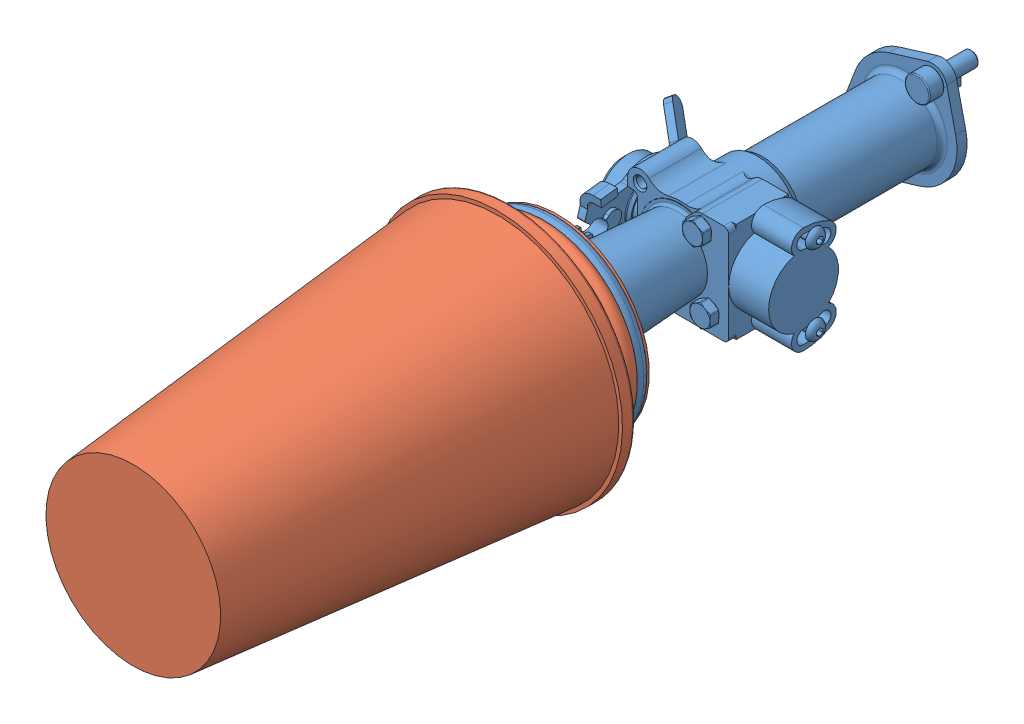
SolidWorks assembly formula_student_throttle_with_air_filter, configuration Default. Lengths in mm.
Overall size (127.6 127.6 349.5).
2 component instances, 2 part files, 2 mates.
Components (placement in the parent):
- formula_student_throttle-1: formula_student_throttle [Default] at (-37.9429 12.0312 36.252) size (78.2 75 188.5)
- Air_filter-1: Air_filter [Default] at (-37.9429 12.0312 96.252) x (0.333112 -0.942887 0) z (-0.942887 -0.333112 0) size (100 170 100)
Mates (geometry in assembly coordinates):
- Concentric1: concentric aligned: circle of formula_student_throttle-1; circle of Air_filter-1
- Coincident1: coincident aligned: plane of formula_student_throttle-1 through (-73.8267 -23.8488 96.252) normal (0 0 -1); plane of Air_filter-1 through (-30.9427 -7.783 96.252) normal (0 0 -1)
